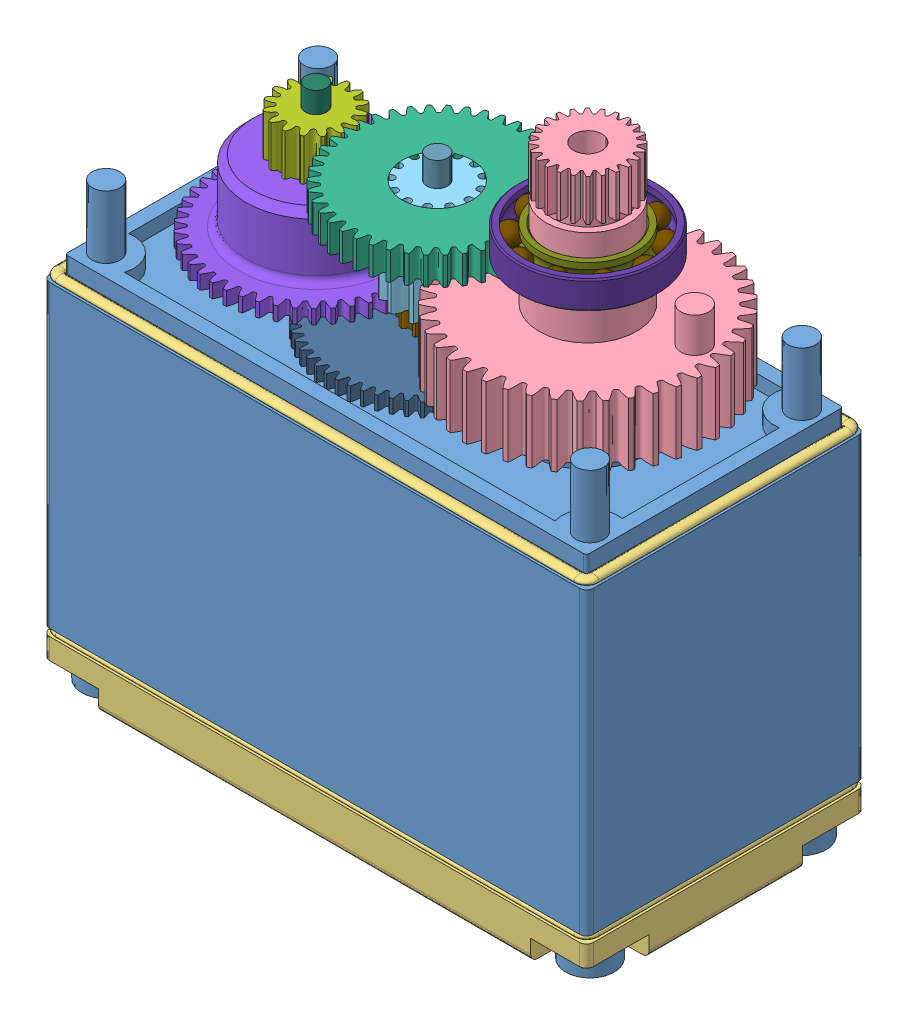
SolidWorks assembly РМ1, configuration Полный. Lengths in mm.
Overall size (41.35 43 23.81).
64 component instances, 28 part files, 82 mates.
Components (placement in the parent):
- Корпус-2: Корпус [По умолчанию] at origin size (39 28 20)
- Плата-1: Плата [По умолчанию] at (0 -10.5 0) x (-1 0 0) z (0 0 -1) size (37.4 1 18.4)
- Крышка-1: Крышка [По умолчанию] at (0 -13 0) x (-1 0 0) z (0 0 1) size (39 4 20)
- G1-1: G1 [Spur01] at (9.6 15.75 0) x (0.200367 0 0.979721) z (0 1 0) size (17.19 17.2 15.5)
- G2-1: G2 [Spur02] at (-1.2 16.75 0) x (-0.962765 0 -0.270339) z (0 1 0) size (5.94 5.98 7)
- G3-1: G3 [G3] at (-1.2 19.25 0) x (-0.270339 0 0.962765) z (0 1 0) size (13.18 13.2 2)
- G4-1: G4 [G4] at (-9.9 18.5 0) x (0.896706 0 0.442627) z (0 -1 0) size (5.33 5.33 4)
- G5-1: G5 [G6] at (-9.9 12.5 0) x (-0.896706 0 -0.442627) z (0 1 0) size (14.38 14.4 5.5)
- G6-1: G6 [G5] at (-1.2 12 0) x (0.073044 0 -0.997329) z (0 -1 0) size (4.1 4.1 2.5)
- G7-1: G7 [G7] at (-1.2 11.25 0) x (0.997329 0 0.073044) z (0 -1 0) size (14.99 15 1)
- G8-1: G8 [П8] at (-9.7 11.25 0) x (-0.199884 0 0.97982) z (0 -1 0) size (2.9 3 1)
- Пласт2-1: Пласт2 [По умолчанию] at (9.6 16.5 0) x (0.200367 0 0.979721) z (0.979721 0 -0.200367) size (10 3.05 9.77)
- Пласт1-1: Пласт1 [По умолчанию] at (9.6 14.5 0) x (-0.200367 0 -0.979721) z (0.979721 0 -0.200367) size (7 1.5 9.77)
- Ось-1: Ось [По умолчанию] at (-1.2 15.75 0) x (0.961755 0 0.273911) z (0.273911 0 -0.961755) size (1.5 12.5 1.5)
- Ось1-1: Ось1 [По умолчанию] at (-9.9 18.75 0) x (0.831133 0 0.556074) z (-0.556074 0 0.831133) size (1.5 6.5 1.5)
- Подшипник_1-1: Подшипник_1 [По умолчанию] at (9.6 13.5 0) size (14.01 2 14.01)
  - Вн_кольцо-1: Вн_кольцо [По умолчанию] at origin size (7 2 7)
  - Нар_кольцо-2: Нар_кольцо [По умолчанию] x (0.605705 0 -0.795689) z (0.795689 0 0.605705) size (10 2 10)
  - Шарик-1: Шарик [По умолчанию] at (-3.9953 0 0.1946) size (1.5 1.5 1.5)
  - Шарик-2: Шарик [По умолчанию] at (-3.3466 0 -2.1909) x (0.809017 0 0.587785) z (-0.587785 0 0.809017) size (1.5 1.5 1.5)
  - Шарик-3: Шарик [По умолчанию] at (-1.4197 0 -3.7396) x (0.309017 0 0.951057) z (-0.951057 0 0.309017) size (1.5 1.5 1.5)
  - Шарик-4: Шарик [По умолчанию] at (1.0495 0 -3.8599) x (-0.309017 0 0.951057) z (-0.951057 0 -0.309017) size (1.5 1.5 1.5)
  - Шарик-5: Шарик [По умолчанию] at (3.1179 0 -2.5058) x (-0.809017 0 0.587785) z (-0.587785 0 -0.809017) size (1.5 1.5 1.5)
  - Шарик-6: Шарик [По умолчанию] at (3.9953 0 -0.1946) x (-1 0 0) z (0 0 -1) size (1.5 1.5 1.5)
  - Шарик-7: Шарик [По умолчанию] at (3.3466 0 2.1909) x (-0.809017 0 -0.587785) z (0.587785 0 -0.809017) size (1.5 1.5 1.5)
  - Шарик-8: Шарик [По умолчанию] at (1.4197 0 3.7396) x (-0.309017 0 -0.951057) z (0.951057 0 -0.309017) size (1.5 1.5 1.5)
  - Шарик-9: Шарик [По умолчанию] at (-1.0495 0 3.8599) x (0.309017 0 -0.951057) z (0.951057 0 0.309017) size (1.5 1.5 1.5)
  - Шарик-10: Шарик [По умолчанию] at (-3.1179 0 2.5058) x (0.809017 0 -0.587785) z (0.587785 0 0.809017) size (1.5 1.5 1.5)
- Винт-1: Винт [По умолчанию] at (17.35 0.5 7.6) x (0.946284 0 0.323336) z (0.323336 0 -0.946284) size (3.5 31 3.5)
- Упл_кольцо-1: Упл_кольцо [По умолчанию] at (17.35 -13.5 7.6) x (0.852696 0 0.522408) z (-0.522408 0 0.852696) size (3.2 0.5 3.2)
- Винт-2: Винт [По умолчанию] at (17.35 0 -7.6) x (0.966388 0 0.257088) z (0.257088 0 -0.966388) size (3.5 31 3.5) (suppressed, hidden)
- Упл_кольцо-2: Упл_кольцо [По умолчанию] at (17.35 -14 -7.6) size (3.2 0.5 3.2) (suppressed, hidden)
- Винт-3: Винт [По умолчанию] at (-17.35 0 -7.6) x (-0.966388 0 0.257088) z (0.257088 0 0.966388) size (3.5 31 3.5) (suppressed, hidden)
- Упл_кольцо-3: Упл_кольцо [По умолчанию] at (-17.35 -14 -7.6) x (-1 0 0) z (0 0 -1) size (3.2 0.5 3.2) (suppressed, hidden)
- Упл_кольцо-4: Упл_кольцо [По умолчанию] at (-17.35 -14 7.6) x (-1 0 0) z (0 0 -1) size (3.2 0.5 3.2) (suppressed, hidden)
- Винт-4: Винт [По умолчанию] at (-17.35 0 7.6) x (-0.966388 0 -0.257088) z (-0.257088 0 0.966388) size (3.5 31 3.5) (suppressed, hidden)
- Основание-1: Основание [По умолчанию] at (0 15 0) x (-1 0 0) z (0 0 -1) size (52 14 20.07) (hidden)
- Подшипник_1-2: Подшипник_1 [По умолчанию] at (9.6 22 0) size (14.01 2 14.01)
  - Вн_кольцо-1: Вн_кольцо [По умолчанию] at origin size (7 2 7)
  - Нар_кольцо-2: Нар_кольцо [По умолчанию] x (0.605705 0 -0.795689) z (0.795689 0 0.605705) size (10 2 10)
  - Шарик-1: Шарик [По умолчанию] at (-3.9953 0 0.1946) size (1.5 1.5 1.5)
  - Шарик-2: Шарик [По умолчанию] at (-3.3466 0 -2.1909) x (0.809017 0 0.587785) z (-0.587785 0 0.809017) size (1.5 1.5 1.5)
  - Шарик-3: Шарик [По умолчанию] at (-1.4197 0 -3.7396) x (0.309017 0 0.951057) z (-0.951057 0 0.309017) size (1.5 1.5 1.5)
  - Шарик-4: Шарик [По умолчанию] at (1.0495 0 -3.8599) x (-0.309017 0 0.951057) z (-0.951057 0 -0.309017) size (1.5 1.5 1.5)
  - Шарик-5: Шарик [По умолчанию] at (3.1179 0 -2.5058) x (-0.809017 0 0.587785) z (-0.587785 0 -0.809017) size (1.5 1.5 1.5)
  - Шарик-6: Шарик [По умолчанию] at (3.9953 0 -0.1946) x (-1 0 0) z (0 0 -1) size (1.5 1.5 1.5)
  - Шарик-7: Шарик [По умолчанию] at (3.3466 0 2.1909) x (-0.809017 0 -0.587785) z (0.587785 0 -0.809017) size (1.5 1.5 1.5)
  - Шарик-8: Шарик [По умолчанию] at (1.4197 0 3.7396) x (-0.309017 0 -0.951057) z (0.951057 0 -0.309017) size (1.5 1.5 1.5)
  - Шарик-9: Шарик [По умолчанию] at (-1.0495 0 3.8599) x (0.309017 0 -0.951057) z (0.951057 0 0.309017) size (1.5 1.5 1.5)
  - Шарик-10: Шарик [По умолчанию] at (-3.1179 0 2.5058) x (0.809017 0 -0.587785) z (0.587785 0 0.809017) size (1.5 1.5 1.5)
- Прокл-1: Прокл [По умолчанию] at (0 -11.75 0) x (1 0 0) z (0 0 1) size (39 0.5 20)
- Прокл-2: Прокл [По умолчанию] at (0 10.25 0) size (39 0.5 20)
- Винт-8: Винт [По умолчанию] at (17.35 0.5 -7.6) x (0.946284 0 0.323336) z (0.323336 0 -0.946284) size (3.5 31 3.5)
- Упл_кольцо-5: Упл_кольцо [По умолчанию] at (17.35 -13.5 -7.6) x (0.852696 0 0.522408) z (-0.522408 0 0.852696) size (3.2 0.5 3.2)
- Винт-9: Винт [По умолчанию] at (-17.35 0.5 7.6) x (0.946284 0 0.323336) z (0.323336 0 -0.946284) size (3.5 31 3.5)
- Упл_кольцо-6: Упл_кольцо [По умолчанию] at (-17.35 -13.5 7.6) x (0.852696 0 0.522408) z (-0.522408 0 0.852696) size (3.2 0.5 3.2)
- Винт-10: Винт [По умолчанию] at (-17.35 0.5 -7.6) x (0.946284 0 0.323336) z (0.323336 0 -0.946284) size (3.5 31 3.5)
- Упл_кольцо-7: Упл_кольцо [По умолчанию] at (-17.35 -13.5 -7.6) x (0.852696 0 0.522408) z (-0.522408 0 0.852696) size (3.2 0.5 3.2)
- Штырь-1: Штырь [По умолчанию] at (15.9682 17 -1.3024) x (-0.26515 0 -0.964207) z (0.964207 0 -0.26515) size (2 7 2)
- Дв_корп-1: Дв_корп [По умолчанию] at (-9.7 0 0) size (17.2 18 17.2)
- Дв_вал-1: Дв_вал [По умолчанию] at (-9.7 7 0) size (1 10 1)
- Дв_крышка-1: Дв_крышка [По умолчанию] at (-9.7 -9.5 0) x (-0.837169 0 -0.546944) z (-0.546944 0 0.837169) size (17.2 2 17.2)
- Птнц_корп-1: Птнц_корп [По умолчанию] at (9.6 5 0) size (10 4 10)
- Птнц_вал-1: Птнц_вал [По умолчанию] at (9.6 12.5 0) x (-0.200367 0 -0.979721) z (0.979721 0 -0.200367) size (4 11 4)
Mates (geometry in assembly coordinates):
- Совпадение7: coincident anti-aligned: plane of Корпус-2 through (0 -10 -32.5618) normal (0 -1 0); plane of Плата-1 through (32.5618 -10 0) normal (0 1 0)
- Совпадение8: coincident anti-aligned: plane of Корпус-2 through (19.5 -11 -9.2) normal (0 0 1); plane of Плата-1 through (32.5618 -10 -9.2) normal (0 0 -1)
- Совпадение9: coincident anti-aligned: plane of Корпус-2 through (18.7 -11 -10) normal (-1 0 0); plane of Плата-1 through (18.7 -10 0) normal (1 0 0)
- Совпадение10: coincident anti-aligned: plane of Корпус-2 through (18.7 -11 -9.2) normal (0 -1 0); plane of Крышка-1 through (19.5 -11 -10) normal (0 1 0)
- Совпадение12: coincident anti-aligned: plane of Корпус-2 through (19.5 -11 -9.2) normal (0 0 1); plane of Крышка-1 through (-18.7 -12 -9.2) normal (0 0 -1)
- Совпадение13: coincident anti-aligned: plane of Корпус-2 through (-18.7 -11 -10) normal (1 0 0); plane of Крышка-1 through (-18.7 -12 9.2) normal (-1 0 0)
- Концентричный1: concentric aligned: cylinder of G2-1 through (-1.2 18.25 0) axis (0 1 0) radius 2.5; cylinder of G3-1 through (-1.2 11.1789 0) axis (0 1 0) radius 2.5
- Совпадение14: coincident anti-aligned: plane of G2-1 through (-1.2 18.25 0) normal (0 1 0); plane of G3-1 through (5.1542 18.25 1.7842) normal (0 -1 0)
- Концентричный2: concentric anti-aligned: cylinder of G4-1 through (-9.9 17.5 0) axis (0 -1 0) radius 2.4; cylinder of G5-1 through (-9.9 9.7118 0) axis (0 1 0) radius 2.4
- Совпадение15: coincident anti-aligned: plane of G4-1 through (-9.9 17.5 0) normal (0 -1 0); plane of G5-1 through (-9.9 17.5 0) normal (0 1 0)
- Концентричный3: concentric aligned: cylinder of G6-1 through (-1.2 11.75 0) axis (0 -1 0) radius 1.75; cylinder of G7-1 through (-1.2 16.6997 0) axis (0 -1 0) radius 1.75
- Совпадение16: coincident anti-aligned: plane of G6-1 through (-7.9234 11.75 -0.4924) normal (0 -1 0); plane of G7-1 through (-1.7478 11.75 7.48) normal (0 1 0)
- Концентричный4: concentric anti-aligned: cylinder of Пласт2-1 through (9.6 8.4289 0) axis (0 1 0) radius 2.5; cylinder of Пласт1-1 through (9.6 16 0) axis (0 -1 0) radius 2.5
- Концентричный5: concentric anti-aligned: cylinder of Пласт2-1 through (4.7014 14.5 1.0018) axis (0 1 0) radius 1.5; cylinder of Пласт1-1 through (4.7014 15.5 1.0018) axis (0 -1 0) radius 1.5
- Совпадение17: coincident anti-aligned: plane of Пласт2-1 through (7.5025 15.5 -10.8175) normal (0 -1 0); plane of Пласт1-1 through (11.8156 15.5 10.9588) normal (0 1 0)
- Концентричный6: concentric aligned: cylinder of G1-1 through (9.6 19 0) axis (0 -1 0) radius 3; cylinder of Пласт2-1 through (9.6 17.5 0) axis (0 -1 0) radius 3
- Совпадение18: coincident aligned: plane of G1-1; plane of Пласт2-1
- Совпадение19: coincident anti-aligned: plane of G1-1 through (9.6 16.5 0) normal (0 -1 0); plane of Пласт2-1 through (7.3352 16.5 -10.9487) normal (0 1 0)
- Концентричный7: concentric anti-aligned: cylinder of G6-1 through (-1.2 15.3713 0) axis (0 -1 0) radius 0.75; cylinder of Ось-1 through (-1.2 9.5 0) axis (0 1 0) radius 0.75
- Совпадение21: coincident aligned: plane of G7-1 through (-1.2 11.25 0) normal (0 -1 0); plane of G8-1 through (-9.7 11.25 0) normal (0 -1 0)
- Совпадение23: coincident: line of G7-1 through (-1.2 -43.75 0) axis (0 1 0); plane of assembly
- Совпадение25: coincident anti-aligned: plane of Корпус-2 through (-1.2 9.5 0) normal (0 1 0); plane of Ось-1 through (-1.2 9.5 0) normal (0 -1 0)
- Совпадение26: coincident anti-aligned: plane of Корпус-2 through (-30.4875 10.75 0) normal (0 1 0); plane of G6-1 through (-1.2 10.75 0) normal (0 -1 0)
- Концентричный8: concentric aligned: cylinder of Корпус-2 through (-1.2 9.5 0) axis (0 1 0) radius 0.75; cylinder of Ось-1 through (-1.2 9.5 0) axis (0 1 0) radius 0.75
- Концентричный9: concentric aligned: cylinder of G4-1 through (-9.9 18.5 0) axis (0 -1 0) radius 0.75; cylinder of Ось1-1 through (-9.9 22 0) axis (0 -1 0) radius 0.75
- Совпадение32: coincident aligned: plane of G6-1; plane of G7-1
- Совпадение33: coincident anti-aligned: plane of G4-1; plane of G5-1
- Концентричный10: concentric aligned: cylinder of G2-1 through (-1.2 11.1287 0) axis (0 1 0) radius 0.75; cylinder of Ось-1 through (-1.2 9.5 0) axis (0 1 0) radius 0.75
- Совпадение34: coincident anti-aligned: plane of G2-1 through (-2.011 13.25 2.8883) normal (0 -1 0); plane of G6-1 through (0.8944 13.25 0.1534) normal (0 1 0)
- Совпадение35: coincident anti-aligned: plane of G2-1; plane of G3-1
- Концентричный11: concentric aligned: cylinder of Корпус-2 through (9.6 14.5 0) axis (0 -1 0) radius 3; cylinder of Подшипник_1-1/Вн_кольцо-1 through (9.6 14.5 0) axis (0 -1 0) radius 3
- Совпадение36: coincident anti-aligned: plane of Корпус-2 through (9.6 12.5 0) normal (0 1 0); plane of Подшипник_1-1/Вн_кольцо-1 through (9.6 12.5 0) normal (0 -1 0)
- Концентричный13: concentric aligned: cylinder of G1-1 through (9.6 16.5 0) axis (0 -1 0) radius 5; cylinder of Подшипник_1-1/Нар_кольцо-2 through (9.6 14.5 0) axis (0 -1 0) radius 5
- Совпадение39: coincident anti-aligned: plane of Пласт1-1 through (11.8156 14.5 10.9588) normal (0 -1 0); plane of Подшипник_1-1/Нар_кольцо-2 through (9.6 14.5 0) normal (0 1 0)
- Сопряжения редуктора5: gear = 5.2 : 16.4 mm: circle of G1-1; circle of G2-1
- Совпадение40: coincident anti-aligned: plane of Корпус-2 through (-14.4414 15.5 0) normal (0 1 0); plane of Ось1-1 through (-9.9 15.5 0) normal (0 -1 0)
- Концентричный16: concentric anti-aligned: cylinder of Корпус-2 through (-9.9 15.5 0) axis (0 1 0) radius 0.75; cylinder of Ось1-1 through (-9.9 22 0) axis (0 -1 0) radius 0.75
- Совпадение41: coincident anti-aligned: plane of Корпус-2 through (-17.7642 16.5 0) normal (0 1 0); plane of G4-1 through (-9.9 16.5 0) normal (0 -1 0)
- Концентричный19: concentric aligned: cylinder of Корпус-2 through (-9.7 11.9142 0) axis (0 -1 0) radius 0.5; circle of G8-1
- Сопряжения редуктора6: gear = 2.5 : 14.5 mm: circle of G7-1; circle of G8-1
- Сопряжения редуктора7: gear = 3.6 : 13.8 mm: circle of G5-1; circle of G6-1
- Сопряжения редуктора8: gear = 4.8 : 12.6 mm: circle of G3-1; circle of G4-1
- Концентричный20: concentric aligned: cylinder of Крышка-1 through (17.35 -13 7.6) axis (0 -1 0) radius 1.6; cylinder of Упл_кольцо-1 through (17.35 -13 7.6) axis (0 -1 0) radius 1.6
- Совпадение43: coincident anti-aligned: plane of Винт-1 through (17.35 -13.5 7.6) normal (0 1 0); plane of Упл_кольцо-1 through (17.35 -13.5 7.6) normal (0 -1 0)
- Концентричный24: concentric aligned: cylinder of Крышка-1 through (17.35 -8.1716 7.6) axis (0 -1 0) radius 1; cylinder of Винт-1 through (17.35 -15 7.6) axis (0 -1 0) radius 0.8
- Совпадение48: coincident anti-aligned: plane of Основание-1 through (0 15 0) normal (0 0 -1); plane of assembly through (0 0 0) normal (0 0 1)
- Концентричный25: concentric aligned: cylinder of Основание-1 through (9.6 23 0) axis (0 -1 0) radius 5; cylinder of Подшипник_1-2/Нар_кольцо-2 through (9.6 23 0) axis (0 -1 0) radius 5
- Совпадение49: coincident anti-aligned: plane of Основание-1 through (9.6 23 0) normal (0 -1 0); plane of Подшипник_1-2/Нар_кольцо-2 through (9.6 23 0) normal (0 1 0)
- Совпадение50: coincident anti-aligned: plane of Основание-1 through (0 15 0) normal (-1 0 0); plane of assembly through (0 0 0) normal (1 0 0)
- Касательность1: tangent: plane of Корпус-2 through (19.5 -11.5 -10) normal (0 -1 0); face of Прокл-1
- Касательность2: tangent: plane of Крышка-1 through (18.7 -12 -9.2) normal (1 0 0); face of Прокл-1
- Касательность3: tangent: plane of Крышка-1 through (-18.7 -12 -9.2) normal (0 0 -1); face of Прокл-1
- Совпадение51: coincident anti-aligned: plane of Корпус-2 through (19.5 11.5 -10) normal (0 1 0); plane of Основание-1 through (-18.7 11.5 9.2) normal (0 -1 0)
- Совпадение52: coincident aligned: plane of Корпус-2 through (0 0 0) normal (0 0 1); plane of Прокл-2 through (0 10.25 0) normal (0 0 1)
- Совпадение53: coincident aligned: plane of Корпус-2 through (0 0 0) normal (1 0 0); plane of Прокл-2 through (0 10.25 0) normal (1 0 0)
- Расстояние1: distance = 0.25 mm aligned: plane of Корпус-2 through (-34.2325 10 0) normal (0 1 0); plane of Прокл-2 through (0 10.25 0) normal (0 1 0)
- Совпадение58: coincident anti-aligned: plane of Крышка-1 through (17.35 -13 7.6) normal (0 -1 0); plane of Упл_кольцо-1 through (17.35 -13 7.6) normal (0 1 0)
- Совпадение59: coincident anti-aligned: plane of Винт-8 through (17.35 -13.5 -7.6) normal (0 1 0); plane of Упл_кольцо-5 through (17.35 -13.5 -7.6) normal (0 -1 0)
- Концентричный29: concentric aligned: cylinder of Крышка-1 through (17.35 -13 -7.6) axis (0 -1 0) radius 1.6; cylinder of Упл_кольцо-5 through (17.35 -13 -7.6) axis (0 -1 0) radius 1.6
- Концентричный30: concentric aligned: cylinder of Крышка-1 through (17.35 -8.1716 -7.6) axis (0 -1 0) radius 1; cylinder of Винт-8 through (17.35 -15 -7.6) axis (0 -1 0) radius 0.8
- Совпадение60: coincident anti-aligned: plane of Крышка-1 through (17.35 -13 -7.6) normal (0 -1 0); plane of Упл_кольцо-5 through (17.35 -13 -7.6) normal (0 1 0)
- Совпадение61: coincident anti-aligned: plane of Винт-9 through (-17.35 -13.5 7.6) normal (0 1 0); plane of Упл_кольцо-6 through (-17.35 -13.5 7.6) normal (0 -1 0)
- Концентричный31: concentric aligned: cylinder of Крышка-1 through (-17.35 -13 7.6) axis (0 -1 0) radius 1.6; cylinder of Упл_кольцо-6 through (-17.35 -13 7.6) axis (0 -1 0) radius 1.6
- Концентричный32: concentric aligned: cylinder of Крышка-1 through (-17.35 -8.1716 7.6) axis (0 -1 0) radius 1; cylinder of Винт-9 through (-17.35 -15 7.6) axis (0 -1 0) radius 0.8
- Совпадение62: coincident anti-aligned: plane of Крышка-1 through (-17.35 -13 7.6) normal (0 -1 0); plane of Упл_кольцо-6 through (-17.35 -13 7.6) normal (0 1 0)
- Совпадение63: coincident anti-aligned: plane of Винт-10 through (-17.35 -13.5 -7.6) normal (0 1 0); plane of Упл_кольцо-7 through (-17.35 -13.5 -7.6) normal (0 -1 0)
- Концентричный33: concentric aligned: cylinder of Крышка-1 through (-17.35 -13 -7.6) axis (0 -1 0) radius 1.6; cylinder of Упл_кольцо-7 through (-17.35 -13 -7.6) axis (0 -1 0) radius 1.6
- Концентричный34: concentric aligned: cylinder of Крышка-1 through (-17.35 -8.1716 -7.6) axis (0 -1 0) radius 1; cylinder of Винт-10 through (-17.35 -15 -7.6) axis (0 -1 0) radius 0.8
- Совпадение64: coincident anti-aligned: plane of Крышка-1 through (-17.35 -13 -7.6) normal (0 -1 0); plane of Упл_кольцо-7 through (-17.35 -13 -7.6) normal (0 1 0)
- Концентричный35: concentric anti-aligned: cylinder of G1-1 through (15.9682 9.6716 -1.3024) axis (0 1 0) radius 1; cylinder of Штырь-1 through (15.9682 20.5 -1.3024) axis (0 -1 0) radius 1
- Совпадение65: coincident aligned: plane of G1-1 through (18.0256 13.5 -1.7232) normal (0 -1 0); plane of Штырь-1 through (15.9682 13.5 -1.3024) normal (0 -1 0)
- Совпадение66: coincident anti-aligned: plane of Корпус-2 through (0 9 -33.3273) normal (0 -1 0); plane of Дв_корп-1 through (-10.2 9 0) normal (0 1 0)
- Концентричный36: concentric aligned: cylinder of Дв_корп-1 through (-9.7 -16.8719 0) axis (0 -1 0) radius 0.5; cylinder of Дв_вал-1 through (-9.7 12 0) axis (0 -1 0) radius 0.5
- Расстояние2: distance = 3 mm aligned: plane of Дв_вал-1 through (-9.7 12 0) normal (0 1 0); plane of Дв_корп-1 through (-10.2 9 0) normal (0 1 0)
- Концентричный37: concentric aligned: cylinder of G8-1 through (-9.7 13.1642 0) axis (0 -1 0) radius 0.5; cylinder of Дв_вал-1 through (-9.7 12 0) axis (0 -1 0) radius 0.5
- Концентричный38: concentric anti-aligned: cylinder of Дв_корп-1 through (-9.7 -16.8719 0) axis (0 -1 0) radius 7.6; cylinder of Дв_крышка-1 through (-9.7 -9 0) axis (0 1 0) radius 7.6
- Совпадение67: coincident anti-aligned: plane of Плата-1 through (32.5618 -10 0) normal (0 1 0); plane of Дв_крышка-1 through (-9.7 -10 0) normal (0 -1 0)
- Концентричный41: concentric anti-aligned: cylinder of Птнц_корп-1 through (9.6 7 0) axis (0 1 0) radius 2; cylinder of Птнц_вал-1 through (9.6 18 0) axis (0 -1 0) radius 2
- Концентричный42: concentric anti-aligned: cylinder of Корпус-2 through (9.6 3.3431 0) axis (0 1 0) radius 2; cylinder of Птнц_вал-1 through (9.6 18 0) axis (0 -1 0) radius 2
- Совпадение71: coincident anti-aligned: plane of Корпус-2 through (0 9 -33.3273) normal (0 -1 0); plane of Птнц_корп-1 through (4.6 9 0) normal (0 1 0)
- Совпадение72: coincident anti-aligned: plane of Пласт1-1 through (9.7506 10.0279 5.7274) normal (0.979721 0 -0.200367); plane of Птнц_вал-1 through (9.0212 16 2.1608) normal (-0.979721 0 0.200367)
- Совпадение73: coincident anti-aligned: plane of Птнц_корп-1 through (7.6 7 0) normal (0 1 0); plane of Птнц_вал-1 through (9.6 7 0) normal (0 -1 0)
